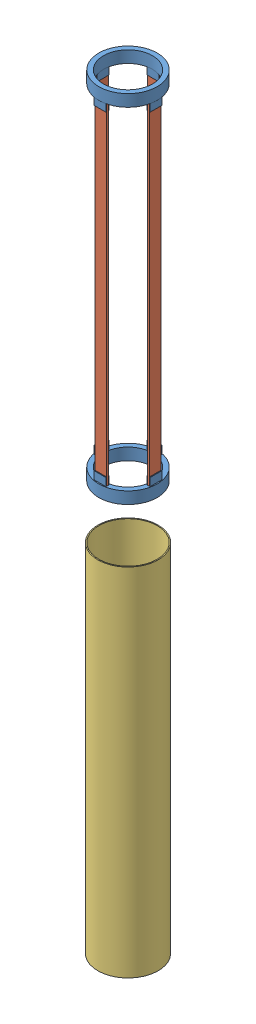
SolidWorks assembly structure_external, configuration Défaut. Lengths in mm.
Overall size (193.05 900.54 193.05).
7 component instances, 3 part files, 15 mates.
Components (placement in the parent):
- ring-2: ring [Défaut] at (-15.0423 -34.6578 147.6) size (147.6 50 147.6)
- rods_carbon-1: rods_carbon [Défaut] at (1414.5089 -1641.7579 78.8136) size (30 840 4)
- rods_carbon-2: rods_carbon [Défaut] at (1414.5089 -1641.7579 212.3864) size (30 840 4)
- rods_carbon-3: rods_carbon [Défaut] at (-83.8287 -1641.7579 -1281.9512) x (0 0 -1) z (1 0 0) size (30 840 4)
- rods_carbon-4: rods_carbon [Défaut] at (53.7441 -1641.7579 1577.1512) x (0 0 1) z (-1 0 0) size (30 840 4)
- ring-3: ring [Défaut] at (-15.0423 865.3422 147.6) x (-1 0 0) z (0 0 1) size (147.6 50 147.6)
- case_rocket-1: case_rocket [Défaut] at (-15.0423 -35.1987 147.6) x (-0.316422 0 -0.948619) z (0.948619 0 -0.316422) size (152.6 900 152.6)
Mates (geometry in assembly coordinates):
- Coïncidente1: coincident anti-aligned: plane of ring-2 through (-15.0423 -4.6578 147.6) normal (0 1 0); plane of rods_carbon-1 through (-30.0423 -4.6578 82.8136) normal (0 -1 0)
- Coïncidente2: coincident anti-aligned: plane of ring-2 through (-15.0423 -4.6578 147.6) normal (0 1 0); plane of rods_carbon-2 through (-30.0423 -4.6578 216.3864) normal (0 -1 0)
- Coïncidente3: coincident anti-aligned: plane of ring-2 through (-15.0423 15.3422 78.8136) normal (0 0 1); plane of rods_carbon-1 through (1414.5089 -1641.7579 78.8136) normal (0 0 -1)
- Coïncidente4: coincident aligned: plane of ring-2 through (-30.0423 15.3422 147.6) normal (-1 0 0); plane of rods_carbon-1 through (-30.0423 835.3422 82.8136) normal (-1 0 0)
- Coïncidente5: coincident aligned: plane of ring-2 through (-30.0423 15.3422 147.6) normal (-1 0 0); plane of rods_carbon-2 through (-30.0423 835.3422 216.3864) normal (-1 0 0)
- Coïncidente6: coincident anti-aligned: plane of ring-2 through (-15.0423 15.3422 216.3864) normal (0 0 -1); plane of rods_carbon-2 through (1414.5089 -1641.7579 216.3864) normal (0 0 1)
- Coïncidente7: coincident anti-aligned: plane of ring-2 through (-79.8287 15.3422 147.6) normal (-1 0 0); plane of rods_carbon-3 through (-79.8287 -1641.7579 -1281.9512) normal (1 0 0)
- Coïncidente8: coincident aligned: plane of ring-2 through (-15.0423 15.3422 162.6) normal (0 0 1); plane of rods_carbon-3 through (-79.8287 835.3422 162.6) normal (0 0 1)
- Coïncidente9: coincident anti-aligned: plane of ring-2 through (-15.0423 -4.6578 147.6) normal (0 1 0); plane of rods_carbon-3 through (-79.8287 -4.6578 162.6) normal (0 -1 0)
- Coïncidente12: coincident anti-aligned: plane of ring-2 through (-15.0423 -4.6578 147.6) normal (0 1 0); plane of rods_carbon-4 through (49.7441 -4.6578 132.6) normal (0 -1 0)
- Coïncidente13: coincident aligned: plane of ring-2 through (-15.0423 15.3422 132.6) normal (0 0 -1); plane of rods_carbon-4 through (49.7441 835.3422 132.6) normal (0 0 -1)
- Coïncidente14: coincident anti-aligned: plane of rods_carbon-4 through (49.7441 835.3422 132.6) normal (0 1 0); plane of ring-3 through (-15.0423 835.3422 147.6) normal (0 -1 0)
- Coïncidente15: coincident aligned: plane of rods_carbon-1 through (-0.0423 835.3422 82.8136) normal (1 0 0); plane of ring-3 through (-0.0423 815.3422 147.6) normal (1 0 0)
- Coïncidente16: coincident anti-aligned: plane of rods_carbon-1 through (1414.5089 -1641.7579 78.8136) normal (0 0 -1); plane of ring-3 through (-15.0423 815.3422 78.8136) normal (0 0 1)
- Coaxiale1: concentric aligned: cylinder of ring-2 through (-15.0423 -4.6578 147.6) axis (0 -1 0) radius 73.8; cylinder of case_rocket-1 through (-15.0423 864.8013 147.6) axis (0 -1 0) radius 73.8
